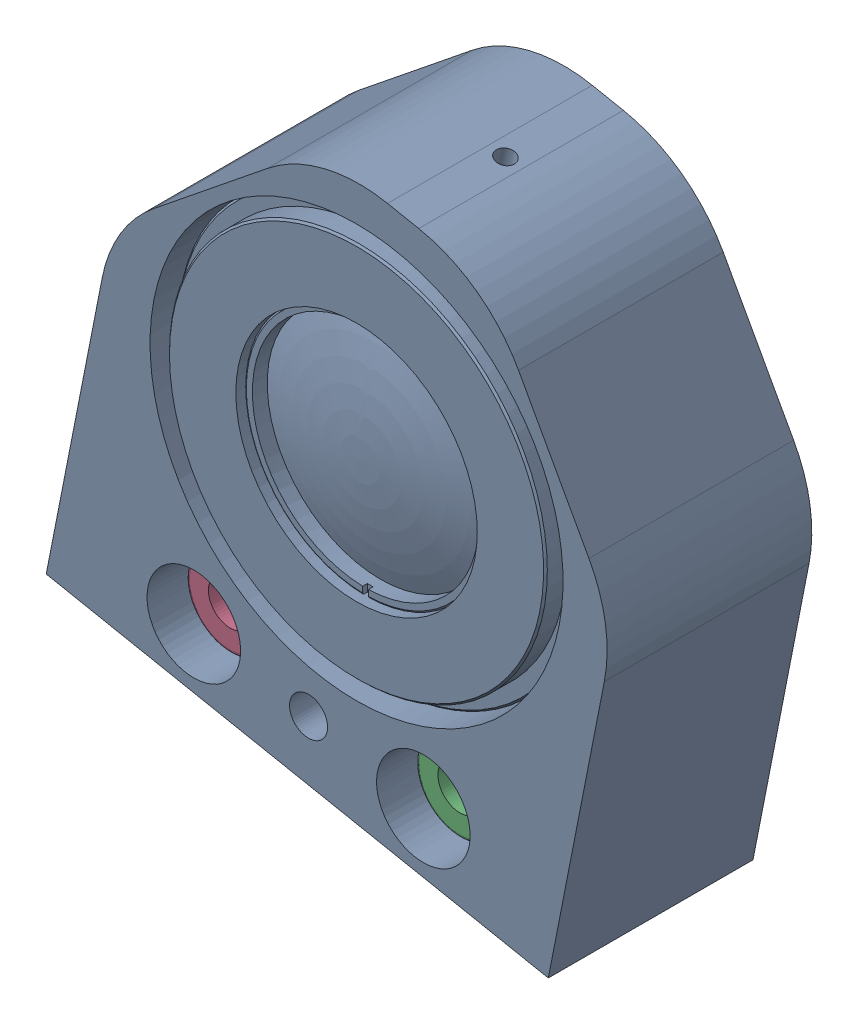
SolidWorks assembly assembly_tube_lens_openSIM_V2.0, configuration Default. Lengths in mm.
Overall size (87.94 89.8 76.1).
5 component instances, 4 part files, 10 mates.
Components (placement in the parent):
- TTL200-A-tubelens_thorlabs_openSIM_V2.0-1: TTL200-A-tubelens_thorlabs_openSIM_V2.0 [Default] at (19.2901 22.7216 48.0953) size (55.88 55.88 28)
- TubeLens_Holder_openSIM_V2.0-1: TubeLens_Holder_openSIM_V2.0 [Default] at (18.4212 18.3063 62.0953) x (0 0 -1) z (0.981183 -0.193082 0) size (28 75 70)
- SSTMH8B_openSIM_V2.0-1: SSTMH8B_openSIM_V2.0 [Default] at (12.7253 -10.6386 42.0953) x (0 0 1) z (0.086199 -0.996278 0) size (11 8 8)
- LMU_N6_openSIM_V2.0-1: LMU_N6_openSIM_V2.0 [Default] at (28.4242 -13.7279 57.0953) x (0 0 -1) z (0.871644 -0.490139 0) size (19 12 12)
- LMU_N6_openSIM_V2.0-2: LMU_N6_openSIM_V2.0 [Default] at (-2.9736 -7.5493 57.0953) x (0 0 -1) z (0.961741 -0.273961 0) size (19 12 12)
Mates (geometry in assembly coordinates):
- Concentric1: concentric anti-aligned: cylinder of TTL200-A-tubelens_thorlabs_20200728-1 through (19.2901 22.7216 62.0953) axis (0 0 1) radius 27.94; cylinder of TubeLens_Holder_V0_20200728-1 through (19.2901 22.7216 62.0953) axis (0 0 -1) radius 28.25
- Coincident1: coincident aligned: plane of TTL200-A-tubelens_thorlabs_20200728-1 through (19.2901 48.5661 62.0953) normal (0 0 1); plane of TubeLens_Holder_V0_20200728-1 through (18.4212 18.3063 62.0953) normal (0 0 1)
- Concentric2: concentric aligned: cylinder of TubeLens_Holder_V0_20200728-1 through (12.7253 -10.6386 62.0953) axis (0 0 -1) radius 2.6; cylinder of SSTMH8B_20200728-1 through (12.7253 -10.6386 50.0953) axis (0 0 -1) radius 2.5
- Coincident2: coincident anti-aligned: plane of TubeLens_Holder_V0_20200728-1 through (12.7253 -10.6386 42.0953) normal (0 0 -1); circle of SSTMH8B_20200728-1
- Concentric3: concentric: cylinder of ? through (15.2934 -26.3602 54.0953) axis (0 0 -1) radius 6.25; cylinder of ? through (15.2934 -26.3602 44.0953) axis (0 0 1) radius 5
- Coincident3: coincident: plane of ? through (15.2934 -26.3602 54.0953) normal (0 0 -1); plane of ? through (17.1192 -21.9016 54.0953) normal (0 0 1)
- Concentric4: concentric anti-aligned: cylinder of TubeLens_Holder_V0_20200728-1 through (-2.9736 -7.5493 38.0953) axis (0 0 1) radius 6.4; cylinder of LMU_N6-2 through (-2.9736 -7.5493 38.0953) axis (0 0 -1) radius 6
- Concentric5: concentric anti-aligned: cylinder of TubeLens_Holder_V0_20200728-1 through (28.4242 -13.7279 38.0953) axis (0 0 1) radius 6.4; cylinder of LMU_N6-1 through (28.4242 -13.7279 38.0953) axis (0 0 -1) radius 6
- Coincident5: coincident aligned: plane of LMU_N6-1 through (29.8946 -11.113 38.0953) normal (0 0 -1); plane of LMU_N6-2 through (-2.1517 -4.664 38.0953) normal (0 0 -1)
- Coincident6: coincident anti-aligned: plane of TubeLens_Holder_V0_20200728-1 through (28.4242 -13.7279 38.0953) normal (0 0 1); plane of LMU_N6-1 through (29.8946 -11.113 38.0953) normal (0 0 -1)
